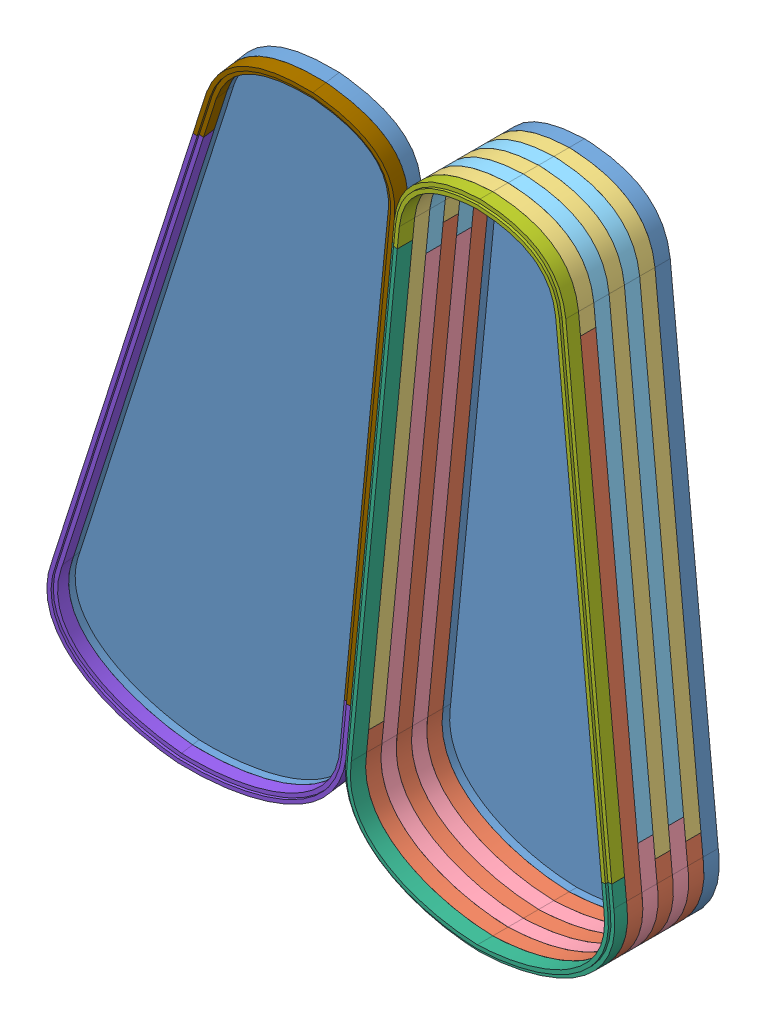
SolidWorks assembly Violin_Case_offset_cut_layers, configuration Default. Lengths in mm.
Overall size (701.69 870.47 175.38).
16 component instances, 9 part files, 44 mates.
Components (placement in the parent):
- Violin_case_bottom-1: Violin_case_bottom [Default] at (239.623 16.2621 649.0359) size (347.88 812.8 19.06)
- offset_1_inch_P1-1: offset_1_inch_P1 [Default] at (239.623 16.2621 668.0959) size (347.88 711.56 19.05)
- offset_1_inch_P2-1: offset_1_inch_P2 [Default] at (239.623 16.2621 668.0859) size (273.56 658.28 19.05)
- offset_2_inch_P1-1: offset_2_inch_P1 [Default] at (239.623 16.2621 687.1459) size (347.88 686.28 19.05)
- offset_2_inch_P2-1: offset_2_inch_P2 [Default] at (239.623 16.2621 687.1359) size (273.56 633 19.05)
- offset_1_inch_P1-2: offset_1_inch_P1 [Default] at (239.623 16.2621 706.1959) size (347.88 711.56 19.05)
- offset_1_inch_P2-2: offset_1_inch_P2 [Default] at (239.623 16.2621 706.1859) size (273.56 658.28 19.05)
- offset_2_inch_P1-2: offset_2_inch_P1 [Default] at (239.623 16.2621 725.2459) size (347.88 686.28 19.05)
- offset_2_inch_P2-2: offset_2_inch_P2 [Default] at (239.623 16.2621 725.2359) size (273.56 633 19.05)
- offset_1_inch_P1-3: offset_1_inch_P1 [Default] at (239.623 16.2621 763.3359) x (-1 0 0) z (0 0 -1) size (347.88 711.56 19.05)
- offset_bottom_edge_P1-1: offset_bottom_edge_P1 [Default] at (239.623 16.2621 763.3459) size (347.88 711.56 19.05)
- offset_1_inch_P2-3: offset_1_inch_P2 [Default] at (239.623 16.2621 763.3459) x (-1 0 0) z (0 0 -1) size (273.56 658.28 19.05)
- offset_bottom_edge_P2-1: offset_bottom_edge_P2 [Default] at (239.623 16.2621 763.3359) size (273.56 658.28 19.05)
- Violin_case_bottom-2: Violin_case_bottom [Default] at (-118.9639 55.6932 764.3929) x (0.972537 -0.194475 -0.127874) z (0.127874 -0.012607 0.99171) size (347.88 812.8 19.06)
- offset_top_edge_P1-1: offset_top_edge_P1 [Default] at (-116.5279 55.453 783.285) x (0.972537 -0.194475 -0.127874) z (0.127874 -0.012607 0.99171) size (347.88 686.28 19.05)
- offset_top_edge_P2-1: offset_top_edge_P2 [Default] at (-116.5279 55.453 783.285) x (0.972537 -0.194475 -0.127874) z (0.127874 -0.012607 0.99171) size (273.56 633 19.05)
Mates (geometry in assembly coordinates):
- Coincident1: coincident: plane of Violin_case_bottom-1 through (356.0294 46.7621 668.0859) normal (0 0 1); plane of offset_1_inch_P2-1 through (315.6698 808.3631 668.0859) normal (0 0 -1)
- Coincident2: coincident: plane of Violin_case_bottom-1 through (406.3105 146.4371 668.0859) normal (0.995175 0.098116 0); plane of offset_1_inch_P2-1 through (403.8183 171.7146 687.1359) normal (0.995175 0.098116 0)
- Coincident3: coincident: line of Violin_case_bottom-1 through (239.623 829.0621 668.0859) axis (0 0 -1); line of offset_1_inch_P2-1 through (239.623 829.0621 687.1359) axis (0 0 -1)
- Coincident4: coincident: plane of offset_1_inch_P1-1 through (130.2548 727.8184 687.1459) normal (0.098116 0.995175 0); plane of offset_1_inch_P2-1 through (130.2548 727.8184 687.1359) normal (-0.098116 -0.995175 0)
- Coincident5: coincident: plane of Violin_case_bottom-1 through (72.9355 146.4371 668.0859) normal (-0.995175 0.098116 0); plane of offset_1_inch_P1-1 through (72.9355 146.4371 687.1459) normal (-0.995175 0.098116 0)
- Coincident6: coincident: plane of offset_1_inch_P2-1 through (315.6698 808.3631 687.1359) normal (0 0 1); plane of offset_2_inch_P2-1 through (315.6698 808.3631 687.1359) normal (0 0 -1)
- Coincident7: coincident: plane of offset_1_inch_P2-1 through (403.8183 171.7146 687.1359) normal (0.995175 0.098116 0); plane of offset_2_inch_P2-1 through (401.3262 196.992 706.1859) normal (0.995175 0.098116 0)
- Coincident8: coincident: line of offset_1_inch_P2-1 through (239.623 829.0621 687.1359) axis (0 0 -1); line of offset_2_inch_P2-1 through (239.623 829.0621 706.1859) axis (0 0 -1)
- Coincident9: coincident: plane of offset_2_inch_P1-1 through (127.7626 702.5409 706.1959) normal (0.098116 0.995175 0); plane of offset_2_inch_P2-1 through (127.7626 702.5409 706.1859) normal (-0.098116 -0.995175 0)
- Coincident10: coincident: plane of offset_1_inch_P1-1 through (72.9355 146.4371 687.1459) normal (-0.995175 0.098116 0); plane of offset_2_inch_P1-1 through (72.9355 146.4371 706.1959) normal (-0.995175 0.098116 0)
- Coincident11: coincident: plane of offset_2_inch_P2-1 through (315.6698 808.3631 706.1859) normal (0 0 1); plane of offset_1_inch_P2-2 through (315.6698 808.3631 706.1859) normal (0 0 -1)
- Coincident12: coincident: line of offset_2_inch_P2-1 through (239.623 829.0621 706.1859) axis (0 0 -1); line of offset_1_inch_P2-2 through (239.623 829.0621 725.2359) axis (0 0 -1)
- Coincident14: coincident: plane of offset_2_inch_P2-1 through (401.3262 196.992 706.1859) normal (0.995175 0.098116 0); plane of offset_1_inch_P2-2 through (403.8183 171.7146 725.2359) normal (0.995175 0.098116 0)
- Coincident15: coincident: plane of offset_1_inch_P1-2 through (130.2548 727.8184 725.2459) normal (0.098116 0.995175 0); plane of offset_1_inch_P2-2 through (130.2548 727.8184 725.2359) normal (-0.098116 -0.995175 0)
- Coincident16: coincident: plane of offset_2_inch_P1-1 through (72.9355 146.4371 706.1959) normal (-0.995175 0.098116 0); plane of offset_1_inch_P1-2 through (72.9355 146.4371 725.2459) normal (-0.995175 0.098116 0)
- Coincident17: coincident: plane of offset_1_inch_P2-2 through (315.6698 808.3631 725.2359) normal (0 0 1); plane of offset_2_inch_P2-2 through (315.6698 808.3631 725.2359) normal (0 0 -1)
- Coincident18: coincident: line of offset_1_inch_P2-2 through (239.623 829.0621 725.2359) axis (0 0 -1); line of offset_2_inch_P2-2 through (239.623 829.0621 744.2859) axis (0 0 -1)
- Coincident19: coincident: plane of offset_1_inch_P2-2 through (403.8183 171.7146 725.2359) normal (0.995175 0.098116 0); plane of offset_2_inch_P2-2 through (401.3262 196.992 744.2859) normal (0.995175 0.098116 0)
- Coincident20: coincident: plane of offset_2_inch_P1-2 through (127.7626 702.5409 744.2959) normal (0.098116 0.995175 0); plane of offset_2_inch_P2-2 through (127.7626 702.5409 744.2859) normal (-0.098116 -0.995175 0)
- Coincident21: coincident: plane of offset_1_inch_P1-2 through (72.9355 146.4371 725.2459) normal (-0.995175 0.098116 0); plane of offset_2_inch_P1-2 through (72.9355 146.4371 744.2959) normal (-0.995175 0.098116 0)
- Coincident22: coincident: plane of offset_2_inch_P2-2 through (315.6698 808.3631 744.2859) normal (0 0 1); plane of offset_1_inch_P1-3 through (123.2165 46.7621 744.2859) normal (0 0 -1)
- Coincident23: coincident: plane of offset_2_inch_P2-2 through (401.3262 196.992 744.2859) normal (0.995175 0.098116 0); plane of offset_1_inch_P1-3 through (406.3105 146.4371 744.2859) normal (0.995175 0.098116 0)
- Coincident24: coincident: line of offset_2_inch_P1-2 through (239.623 16.2621 744.2959) axis (0 0 -1); line of offset_1_inch_P1-3 through (239.623 16.2621 744.2859) axis (0 0 1)
- Coincident25: coincident: plane of offset_2_inch_P1-2 through (356.0294 46.7621 744.2959) normal (0 0 1); plane of ? through (163.9235 808.2419 729.2081) normal (0 0 -1)
- Coincident26: coincident: plane of offset_2_inch_P1-2 through (72.9355 146.4371 744.2959) normal (-0.995175 0.098116 0); plane of ? through (78.2671 196.8708 729.2081) normal (-0.995175 0.098116 0)
- Coincident27: coincident: line of offset_2_inch_P2-2 through (239.623 829.0621 744.2859) axis (0 0 -1); line of offset_1_inch_P2-3 through (239.623 829.0621 744.2959) axis (0 0 1)
- Coincident28: coincident: plane of offset_2_inch_P1-2 through (356.0294 46.7621 744.2959) normal (0 0 1); plane of offset_1_inch_P2-3 through (163.5762 808.3631 744.2959) normal (0 0 -1)
- Coincident29: coincident: plane of offset_2_inch_P1-2 through (72.9355 146.4371 744.2959) normal (-0.995175 0.098116 0); plane of offset_1_inch_P2-3 through (75.4276 171.7146 744.2959) normal (-0.995175 0.098116 0)
- Coincident30: coincident: line of offset_2_inch_P2-2 through (239.623 829.0621 744.2859) axis (0 0 -1); line of offset_1_inch_P2-3 through (239.623 829.0621 744.2959) axis (0 0 1)
- Coincident31: coincident: plane of offset_bottom_edge_P1-1 through (356.0294 46.7621 763.3459) normal (0 0 -1); plane of offset_1_inch_P2-3 through (163.5762 808.3631 763.3459) normal (0 0 1)
- Coincident32: coincident: plane of offset_bottom_edge_P1-1 through (72.9355 146.4371 782.3959) normal (-0.995175 0.098116 0); plane of offset_1_inch_P2-3 through (75.4276 171.7146 744.2959) normal (-0.995175 0.098116 0)
- Coincident33: coincident: line of offset_1_inch_P1-3 through (239.623 16.2621 744.2859) axis (0 0 1); line of offset_bottom_edge_P1-1 through (239.623 16.2621 779.2209) axis (0 0 -1)
- Coincident34: coincident: plane of offset_1_inch_P1-3 through (123.2165 46.7621 763.3359) normal (0 0 1); plane of offset_bottom_edge_P2-1 through (315.6698 808.3631 763.3359) normal (0 0 -1)
- Coincident35: coincident: plane of offset_1_inch_P1-3 through (406.3105 146.4371 744.2859) normal (0.995175 0.098116 0); plane of offset_bottom_edge_P2-1 through (403.8183 171.7146 782.3859) normal (0.995175 0.098116 0)
- Coincident36: coincident: line of offset_1_inch_P2-3 through (239.623 829.0621 744.2959) axis (0 0 1); line of offset_bottom_edge_P2-1 through (239.623 829.0621 779.2109) axis (0 0 -1)
- Coincident37: coincident: plane of Violin_case_bottom-2; plane of ? through (-189.6568 219.7274 919.3301) normal (0 0 -1)
- Coincident38: coincident: plane of Violin_case_bottom-2; plane of ? through (-472.7507 319.4025 938.3801) normal (-0.995175 0.098116 0)
- Coincident39: coincident: plane of Violin_case_bottom-2 through (2.6131 62.73 768.0151) normal (0.127874 -0.012607 0.99171); plane of offset_top_edge_P1-1 through (2.6131 62.73 768.0151) normal (-0.127874 0.012607 -0.99171)
- Coincident40: coincident: plane of Violin_case_bottom-2 through (-253.3218 215.5487 802.9588) normal (-0.948763 0.289772 0.12602); plane of offset_top_edge_P1-1 through (-250.8858 215.3086 821.8509) normal (-0.948763 0.289772 0.12602)
- Coincident41: coincident: line of Violin_case_bottom-2 through (-116.5279 55.453 783.285) axis (-0.127874 0.012607 -0.99171); line of offset_top_edge_P1-1 through (-114.0919 55.2129 802.1771) axis (-0.127874 0.012607 -0.99171)
- Coincident42: coincident: plane of Violin_case_bottom-2 through (2.6131 62.73 768.0151) normal (0.127874 -0.012607 0.99171); plane of offset_top_edge_P2-1 through (111.4746 817.5773 763.5744) normal (-0.127874 0.012607 -0.99171)
- Coincident43: coincident: plane of Violin_case_bottom-2 through (70.8976 150.7155 760.3289) normal (0.986925 -0.097302 -0.128494); plane of offset_top_edge_P2-1 through (78.3179 201.0302 779.2209) normal (0.986925 -0.097302 -0.128494)
- Coincident44: coincident: line of Violin_case_bottom-2 through (41.5417 852.6687 773.0378) axis (-0.127874 0.012607 -0.99171); line of offset_top_edge_P2-1 through (43.9777 852.4285 791.9299) axis (-0.127874 0.012607 -0.99171)
- Coincident45: coincident: line of offset_bottom_edge_P1-1 through (130.2548 727.8184 779.2209) axis (-0.098116 -0.995175 0); line of offset_top_edge_P2-1 through (78.3179 201.0302 779.2209) axis (0.098116 0.995175 0)
